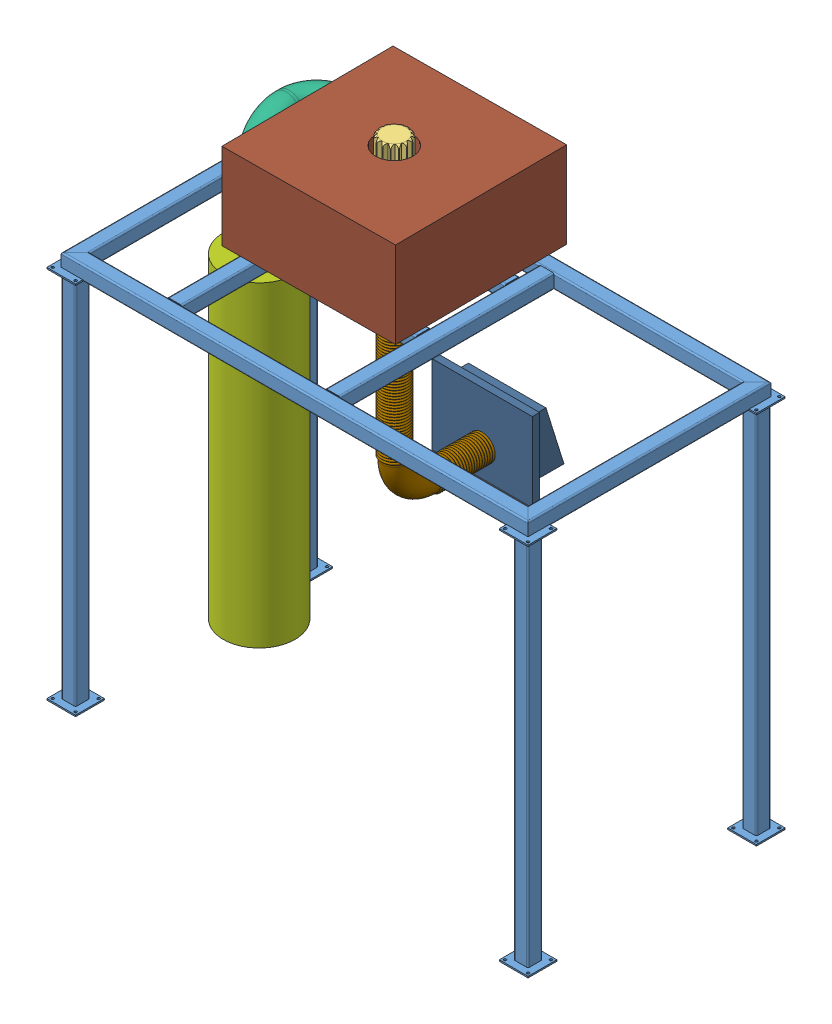
SolidWorks assembly Final Assembly, configuration Default. Lengths in mm.
Overall size (3411.41 3370.35 2165).
12 component instances, 11 part files, 26 mates.
Components (placement in the parent):
- Support Structure-1: Support Structure [Default<As Machined>] at (1194.0684 -99.1228 2972.3895) size (3350 2700 1790)
- Centrifugal Pump Assembly-1: Centrifugal Pump Assembly [Default] at (2896.5465 2572.3409 1369.9757) x (0 0 1) z (0 -1 0) size (845 784 670.35)
  - Centrifugal Pump-1: Centrifugal Pump [Default] at (186.0108 748.9336 -335.1444) size (845 784 415)
  - Motor for Pump-1: Motor for Pump [Default] at (448.6341 648.8338 -603.1444) x (-0.894995 0.446076 0) z (0 0 1) size (260 260 300.35)
  - Impeller-1: Impeller [Default] at (448.6341 648.8338 -310.1444) x (-0.826457 0.562999 0) z (0 0 1) size (398.27 398.27 194.27)
- Convergent Pipe-1: Convergent Pipe [Default] at (1593.7127 2827.4852 1487.3895) x (0 0 -1) z (1 0 0) size (280 240 270.01)
- Bemd Pipe-1: Bemd Pipe [Default] at (1373.9768 2052.6509 1885.7177) size (377 889.63 611.55)
- Bag Filter-1: Bag Filter [Default] at (1373.9768 -149.3491 1885.7177) x (0.755236 0 -0.655453) z (0 1 0) size (500 500 2352)
- Joint Pipe-1: Joint Pipe [Default] at (2247.7127 2682.4852 1817.3895) x (0.290442 0 -0.956892) z (0 -1 0) size (280 280 310)
- Flexible Pipe-2: Flexible Pipe [Default] at (2247.7127 2262.4852 1817.3895) x (0 0 -1) z (1 0 0) size (800 1481.9 280)
- Inlet Hood-1: Inlet Hood [Default] at (2247.7127 1067.4852 1207.3895) x (-1 0 0) z (0 0 -1) size (700 550 300)
- Enclosure-1: Enclosure [Default] at (2247.7127 2507.4852 1818.6098) x (-0.999973 0 0.007347) z (0 1 0) size (1200 1200 600)
Mates (geometry in assembly coordinates):
- Coincident1: coincident: plane of Support Structure-1 through (1822.7127 2507.4852 1662.3895) normal (0 1 0); plane of Centrifugal Pump Assembly-1/Centrifugal Pump-1 through (2147.6129 2507.4852 1555.9864) normal (0 -1 0)
- Coincident3: coincident anti-aligned: plane of Support Structure-1 through (1872.7127 2497.4852 2972.3895) normal (1 0 0); plane of Centrifugal Pump Assembly-1/Centrifugal Pump-1 through (1872.7127 2507.4852 1882.3895) normal (-1 0 0)
- Coincident4: coincident anti-aligned: plane of Support Structure-1 through (1822.7127 2417.4852 2192.3895) normal (0 0 -1); plane of Centrifugal Pump Assembly-1/Centrifugal Pump-1 through (2312.7127 2507.4852 2192.3895) normal (0 0 1)
- Coincident5: coincident anti-aligned: plane of Centrifugal Pump Assembly-1/Centrifugal Pump-1 through (1863.7127 2907.4852 1555.9864) normal (-1 0 0); plane of Convergent Pipe-1 through (1863.7127 2827.4852 1487.3895) normal (1 0 0)
- Coincident6: coincident aligned: plane of Centrifugal Pump Assembly-1/Centrifugal Pump-1 through (1863.7127 2922.4852 1347.3895) normal (0 0 -1); plane of Convergent Pipe-1 through (1863.7127 2707.4852 1347.3895) normal (0 0 -1)
- Coincident7: coincident: plane of Centrifugal Pump Assembly-1/Centrifugal Pump-1 through (1863.7127 2922.4852 1347.3895) normal (0 1 0); plane of Convergent Pipe-1 through (1863.7127 2947.4852 1627.3895) normal (0 1 0)
- Coincident8: coincident: plane of Centrifugal Pump Assembly-1/Centrifugal Pump-1 through (1863.7127 2747.4852 1377.3895) normal (0 1 0); plane of Convergent Pipe-1 through (1863.7127 2747.4852 1587.3895) normal (0 1 0)
- Coincident10: coincident: plane of Convergent Pipe-1 through (1593.7127 2827.4852 1487.3895) normal (-1 0 0); plane of Bemd Pipe-1 through (1648.9768 2829.6509 1485.7177) normal (1 0 0)
- Parallel3: parallel anti-aligned: plane of Convergent Pipe-1 through (1593.7127 2827.4852 1487.3895) normal (-1 0 0); plane of Bemd Pipe-1 through (1648.9768 2829.6509 1485.7177) normal (1 0 0)
- Tangent2: tangent: plane of assembly; plane of Convergent Pipe-1 through (1593.7127 2827.4852 1487.3895) normal (-1 0 0); face of Bemd Pipe-1
- Concentric1: concentric: circle of Convergent Pipe-1; circle of Bemd Pipe-1
- Lock1: lock: unknown of Convergent Pipe-1; unknown of Bemd Pipe-1
- Parallel4: parallel: plane of Support Structure-1 through (4321.3571 -192.5148 2972.3895) normal (0 -1 0); plane of Bemd Pipe-1 through (1373.9768 2052.6509 1885.7177) normal (0 -1 0)
- Concentric2: concentric anti-aligned: cylinder of Bemd Pipe-1 through (1373.9768 2052.6509 1885.7177) axis (0 1 0) radius 102; cylinder of Bag Filter-1 through (1373.9768 2202.6509 1885.7177) axis (0 -1 0) radius 102
- Coincident12: coincident anti-aligned: plane of Bemd Pipe-1 through (1373.9768 2052.6509 1885.7177) normal (0 -1 0); plane of Bag Filter-1 through (1373.9768 2052.6509 1885.7177) normal (0 1 0)
- Concentric3: concentric anti-aligned: cylinder of Centrifugal Pump Assembly-1/Centrifugal Pump-1 through (2247.7127 2799.4852 1817.3895) axis (0 -1 0) radius 100; cylinder of Joint Pipe-1 through (2247.7127 2372.4852 1817.3895) axis (0 1 0) radius 98
- Coincident13: coincident anti-aligned: plane of Centrifugal Pump Assembly-1/Centrifugal Pump-1 through (2247.7127 2682.4852 1817.3895) normal (0 -1 0); plane of Joint Pipe-1 through (2247.7127 2682.4852 1817.3895) normal (0 1 0)
- Concentric5: concentric anti-aligned: cylinder of Joint Pipe-1 through (2247.7127 2372.4852 1817.3895) axis (0 1 0) radius 98; cylinder of Flexible Pipe-2 through (2247.7127 2372.4852 1817.3895) axis (0 -1 0) radius 102.0417
- Coincident17: coincident anti-aligned: plane of Joint Pipe-1 through (2247.7127 2372.4852 1817.3895) normal (0 -1 0); plane of Flexible Pipe-2 through (2247.7127 2372.4852 1817.3895) normal (0 1 0)
- Parallel8: parallel aligned: plane of Support Structure-1 through (4332.7127 2497.4852 1332.3895) normal (0 0 -1); plane of Flexible Pipe-2 through (2247.7127 982.4852 1157.3895) normal (0 0 -1)
- Concentric6: concentric aligned: cylinder of Flexible Pipe-2 through (2247.7127 982.4852 1577.3895) axis (0 0 -1) radius 80; cylinder of Inlet Hood-1 through (2247.7127 982.4852 1207.3895) axis (0 0 -1) radius 80
- Parallel9: parallel aligned: plane of Support Structure-1 through (1232.7127 -182.5148 1422.3895) normal (1 0 0); plane of Inlet Hood-1 through (2597.7127 792.4852 1157.3895) normal (1 0 0)
- Coincident21: coincident aligned: plane of Flexible Pipe-2 through (2247.7127 982.4852 1157.3895) normal (0 0 -1); plane of Inlet Hood-1 through (2247.7127 1067.4852 1157.3895) normal (0 0 -1)
- Parallel10: parallel anti-aligned: plane of Support Structure-1 through (4332.7127 2407.4852 1422.3895) normal (0 -1 0); plane of Inlet Hood-1 through (2597.7127 1342.4852 1157.3895) normal (0 1 0)
- Coincident25: coincident anti-aligned: plane of Support Structure-1 through (1862.7127 2507.4852 2972.3895) normal (0 1 0); plane of Enclosure-1 through (2247.7127 2507.4852 1818.6098) normal (0 -1 0)
- Concentric7: concentric anti-aligned: cylinder of Centrifugal Pump Assembly-1/Motor for Pump-1 through (2247.7127 2925.4852 1818.6098) axis (0 1 0) radius 102.5; cylinder of Enclosure-1 through (2247.7127 3107.4852 1818.6098) axis (0 -1 0) radius 130
